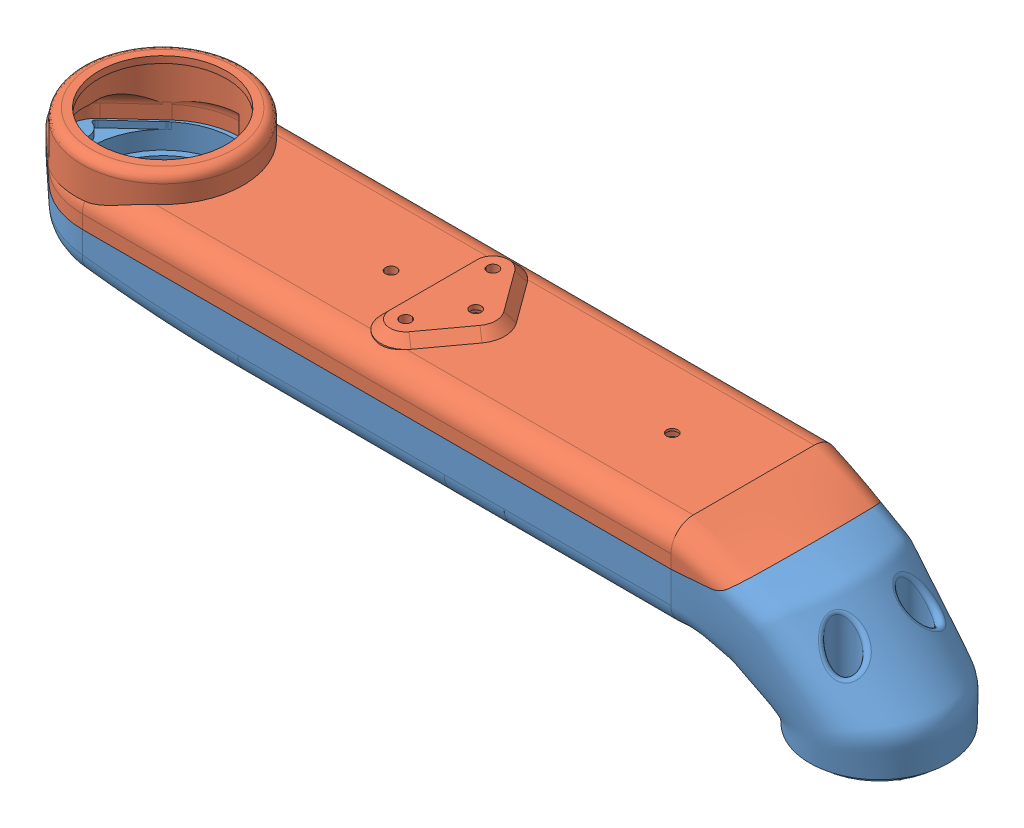
SolidWorks assembly Assem2, configuration Default. Lengths in mm.
Overall size (198.25 43.5 37.06).
2 component instances, 2 part files, 3 mates.
Components (placement in the parent):
- upper leg module shell base-1: upper leg module shell base [Default] at (64.5696 101.4754 134.999) x (0 0 1) z (-1 0 0) size (37.02 37.51 198.25)
- Part1-1: Part1 [Default] at (58.1988 107.4754 134.999) size (170.13 17.96 37.06)
Mates (geometry in assembly coordinates):
- Coincident1: coincident: plane of upper leg module shell base-1 through (24.5696 107.4754 153.499) normal (0 1 0); plane of Part1-1 through (0.0515 107.4754 134.999) normal (0 -1 0)
- Coincident2: coincident: line of upper leg module shell base-1 through (4.1397 107.4754 153.499) axis (1 0 0); plane of Part1-1 through (77.4215 115.4754 153.499) normal (0 0 1)
- Coincident4: coincident anti-aligned: plane of upper leg module shell base-1 through (95.0825 65.1116 116.4949) normal (-0.642788 0.766044 0); plane of Part1-1 through (94.2983 64.4537 116.449) normal (0.642788 -0.766044 0)
